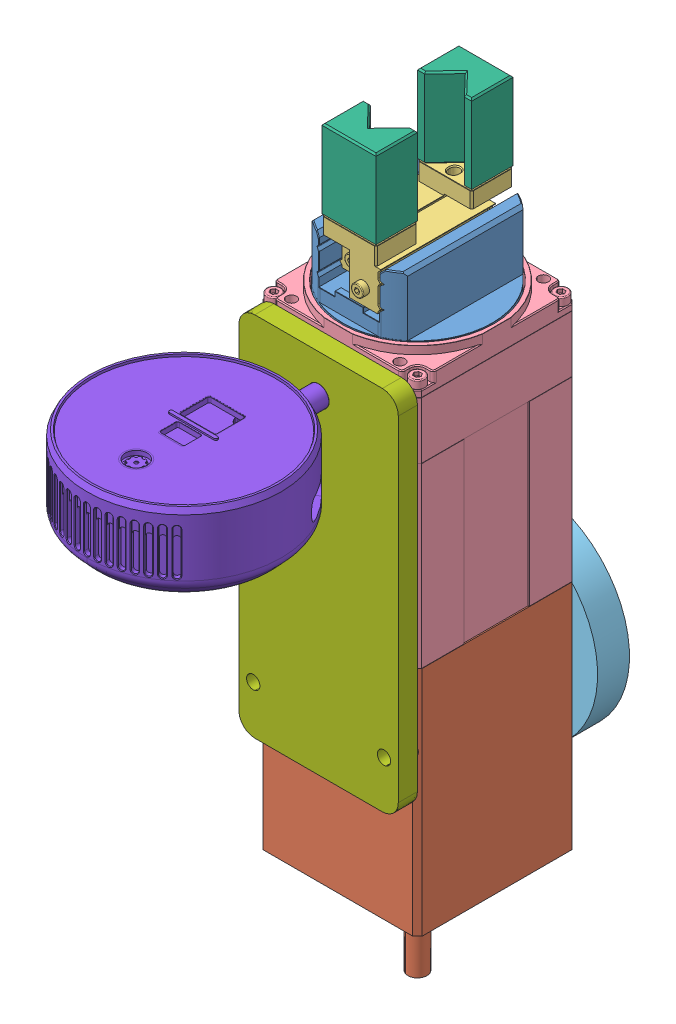
SolidWorks assembly RGI14_cBrida_UR3e.stp, configuration Default. Lengths in mm.
Overall size (122.02 236.5 138.67).
11 component instances, 8 part files, 7 mates.
Components (placement in the parent):
- RGI14.stp-1: RGI14.stp [Default] at (0 79.3 35) x (0 0 -1) z (1 0 0) size (50 211.5 50)
  - U tray_0.stp-1: U tray_0.stp [Default] at origin size (47 25.2 47)
  - bot_0.stp-1: bot_0.stp [Default] at (0 -48 0) x (0 0 -1) z (1 0 0) size (50 106.2 50)
  - finger_1_0.stp-1: finger_1_0.stp [Default] at origin size (40 19.5 18.5)
  - main body_0.stp-1: main body_0.stp [Default] at origin size (49.8 81.3 49.9)
  - finger_1_0.stp-2: finger_1_0.stp [Default] x (-1 0 0) z (0 0 -1) size (40 19.5 18.5)
- Flange_UR3e_Gripper.stp-1: Flange_UR3e_Gripper.stp [Default] at origin size (63 63 10)
- Fingertip.stp-1: Fingertip.stp [Default] at (0 153 50) x (0 0 -1) z (0 -1 0) size (13 17 25)
- Fingertip.stp-2: Fingertip.stp [Default] at (0 128 20) x (0 0 1) z (0 1 0) size (13 17 25)
- Brida_RGI14_L515.stp-1: Brida_RGI14_L515.stp [Default] at (0 42.5 63) x (-1 0 0) z (0 0 1) size (50 115 6)
- Intel_RealSense_L515_Housing_reduced.stp-1: Intel_RealSense_L515_Housing_reduced.stp [Default] at (-0.0477 99.9446 108.15) x (-1 0 0) z (0 1 0) size (122.02 72.67 26.05)
Mates (geometry in assembly coordinates):
- Coincident5: coincident anti-aligned: plane of RGI14.stp-1/bot_0.stp-1 through (25 -0.8 60) normal (0 0 1); plane of Brida_RGI14_L515.stp-1 through (0 42.5 60) normal (0 0 -1)
- Coincident6: coincident aligned: plane of RGI14.stp-1/bot_0.stp-1 through (25 -0.8 10) normal (1 0 0); plane of Brida_RGI14_L515.stp-1 through (25 -15 66) normal (1 0 0)
- Concentric1: concentric anti-aligned: circle of RGI14.stp-1/bot_0.stp-1; circle of Brida_RGI14_L515.stp-1
- Coincident8: coincident anti-aligned: plane of Brida_RGI14_L515.stp-1 through (0 42.5 66) normal (0 0 1); plane of Intel_RealSense_L515_Housing_reduced.stp-1 through (0 88 66) normal (0 0 -1)
- Perpendicular1: perpendicular: plane of Brida_RGI14_L515.stp-1 through (0 42.5 66) normal (0 0 1); plane of Intel_RealSense_L515_Housing_reduced.stp-1 through (-0.0477 99.3446 108.15) normal (0 1 0)
- Concentric2: concentric anti-aligned: circle of Brida_RGI14_L515.stp-1; circle of Intel_RealSense_L515_Housing_reduced.stp-1
- Parallel10: parallel aligned: plane of Brida_RGI14_L515.stp-1 through (25 100 66) normal (0 1 0); plane of Intel_RealSense_L515_Housing_reduced.stp-1 through (-0.0477 99.3446 108.15) normal (0 1 0)
